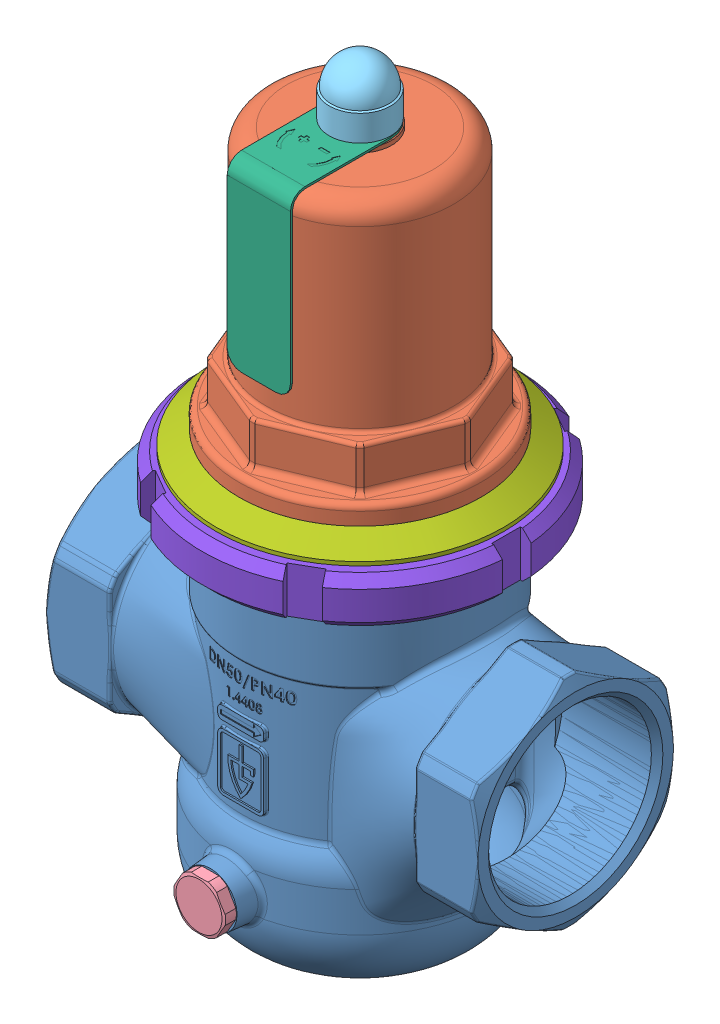
SolidWorks assembly 481mGFO-LP-40-F+F-40+40, configuration Standard. Lengths in mm.
Overall size (151.01 258.7 112).
10 component instances, 8 part files, 0 mates.
Components (placement in the parent):
- 04810500008-2: 04810500008 [Standard] at origin size (151.01 123 104)
- 04810500002-1: 04810500002 [Standard] at (0 67.5 0) size (84 101 84)
- 00000001103-1: 00000001103 [Standard] at (0 -40 -51.1216) x (1 0 0) z (0 -1 0) size (14.38 1.78 14.38)
- 00000001106-1: 00000001106 [Standard] at (0 -40 -56) x (1 0 0) z (0 1 0) size (18 14 17)
- 00000000047-1: 00000000047 [Standard] at (0 169.2 0) size (21.3 19.5 21.3)
- 06820500013-1: 06820500013 [Standard] at (0 169.2 0) x (0 0 1) z (-1 0 0) size (45.7 62 22)
- 06820500006-1: 06820500006 [Standard] at (0 62 0) size (100 14 100)
- 06820500005-1: 06820500005 [Standard] at (0 43.5 0) size (109.04 25.5 109.5)
- 00000001103-4: 00000001103 [Standard] at (0 -40 51.1216) x (1 0 0) z (0 1 0) size (14.38 1.78 14.38)
- 00000001106-3: 00000001106 [Standard] at (0 -40 56) x (1 0 0) z (0 -1 0) size (18 14 17)
